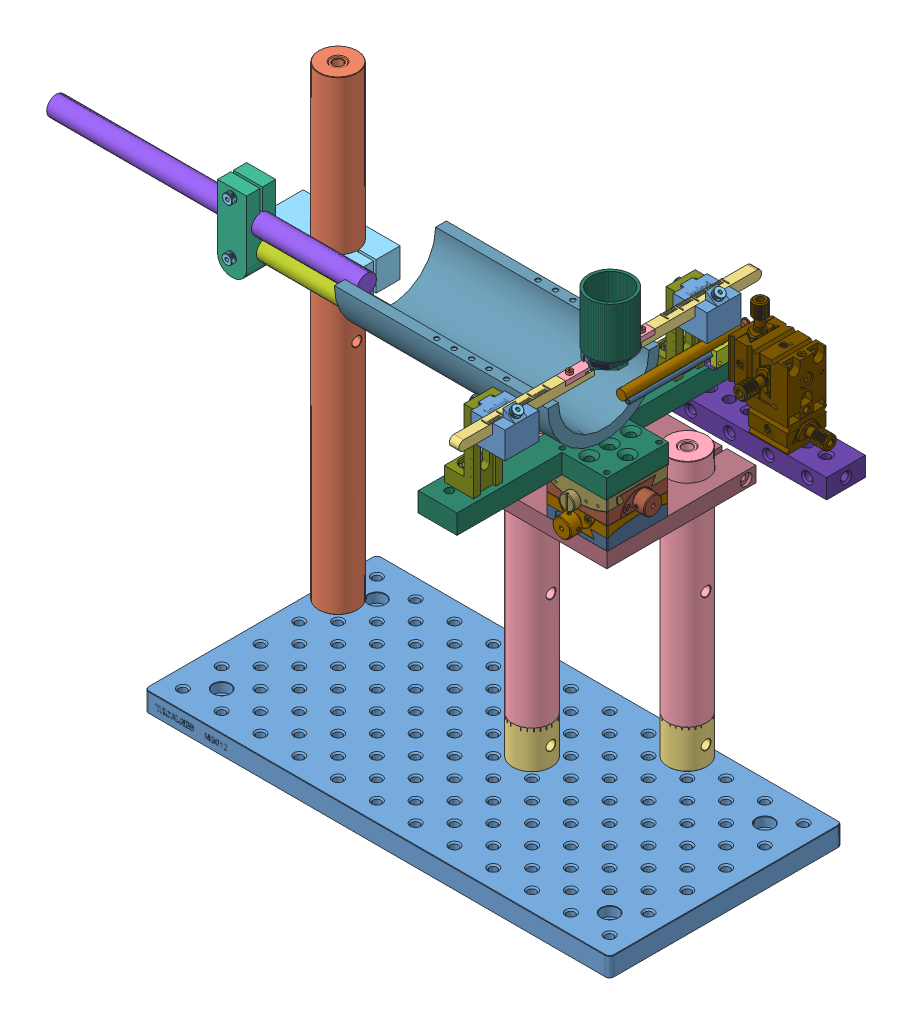
SolidWorks assembly Anesthetized Imaging Rig, configuration Default. Lengths in mm.
Overall size (450.58 317.5 198.19).
59 component instances, 33 part files, 37 mates.
Components (placement in the parent):
- THORLABS_baseplate_MB612-1: THORLABS_baseplate_MB612 [Default] at origin size (304.8 12.7 152.4)
- THORLABS_leg_RS12-1: THORLABS_leg_RS12 [Default] at (-139.7 12.7 -38.1) size (25.57 304.8 25.37)
- THORLABS_leg_RS1-1: THORLABS_leg_RS1 [Default] at (9.07 28.0621 -12.896) size (25.57 25.4 25.37)
- THORLABS_leg_RS1-2: THORLABS_leg_RS1 [Default] at (59.87 28.5325 -63.696) size (25.57 25.4 25.37)
- THORLABS_leg_RS6-1: THORLABS_leg_RS6 [Default] at (11.2798 112.6585 -13.2657) x (-0.009302 0 -0.999957) z (0.999957 0 -0.009302) size (25.37 152.4 25.57)
- THORLABS_leg_RS6-2: THORLABS_leg_RS6 [Default] at (62.0872 113.887 -64.0839) x (0.003562 0 -0.999994) z (0.999994 0 0.003562) size (25.37 152.4 25.57)
- bar_clamp_2-1: bar_clamp_2 [Default] at (-147.32 216.8443 -38.1) x (0 0 -1) z (-1 0 0) size (33.02 19.05 63.5)
- bar_clamp_1-1: bar_clamp_1 [Default] at (-173.6219 195.8875 -12.165) x (0 0 -1) z (1 0 0) size (19.05 50.8 19.05)
- horizontal_bar_2-1: horizontal_bar_2 [Default] at (-160.884 213.6676 -12.1346) x (0 -0.063873 0.997958) z (1 0 0) size (12.7 12.7 152.4)
- horizontal_bar_1-3: horizontal_bar_1 [Default] at (-298.1789 226.3675 -12.165) x (0 0 -1) z (1 0 0) size (12.7 12.7 203.2)
- GOH-40A51UU-1: GOH-40A51UU [Default] at (64.8145 124.6763 -9.8152) x (0 0 1) z (0 -1 0) size (50.27 46.7 15)
  - GOH-8UU-C1B-S02-1: GOH-8UU-C1B-S02 [Default] at origin size (50 40 12.5)
  - GOH-8UU-C1B-S01-1: GOH-8UU-C1B-S01 [Default] x (0 1 0) z (0 0 1) size (46.7 40.57 13)
- GOH-40A35RUU-1: GOH-40A35RUU [Default] at (70.0565 196.9888 -9.6675) x (-1 0 0) z (0 1 0) size (50.47 46.7 16)
  - GOH40A35RUU-M02-13001-S02-1: GOH40A35RUU-M02-13001-S02 [Default] at origin size (50 40 13.5)
  - GOH40A35RUU-M02-13001-S01-1: GOH40A35RUU-M02-13001-S01 [Default] at origin size (40.85 46.7 14)
- gonio_platform-3: gonio_platform [Default] at (35.95 166.2256 -38.45) size (97.5 10 97.5)
- tray-1: tray [Default] at (64.7511 264.1373 -15.4304) x (0 0 -1) z (-1 0 0) size (73.33 36.66 139.7)
- headbar_platform-1: headbar_platform [Default] at (31.035 205.2247 10.5881) size (54.61 12.7 178.16)
- headbar_post-1: headbar_post [Default] at (34.0613 217.9514 46.9863) size (19.05 50.8 19.07)
- headbar_post-2: headbar_post [Default] at (34.0613 218.2062 -85.4493) size (19.05 50.8 19.07)
- horizontal support-1: horizontal support [Default] at (78.5112 190.7326 -88.729) x (0.999996 0 -0.00275) z (0.00275 0 0.999996) size (127 12.7 25.4)
- MT-XYZ-1: MT-XYZ [Default] at (116.3607 203.4326 -88.7982) x (0 0 -1) z (0 -1 0) size (45.44 54.1 66.8)
- headbar finished assem-1: headbar finished assem [Default] at (64.2238 260.2066 67.755) x (0 0 -1) z (1 0 0) size (88.9 24.55 25.25)
  - bar rest-1: bar rest [Default] at origin size (22.23 22.61 24.77)
  - 91292A003_TYPE 18-8 SS SOCKET HEAD CAP SCREW-1: 91292A003_TYPE 18-8 SS SOCKET HEAD CAP SCREW [91292A003] at (53.4332 5.7455 0) x (1 0 0) z (0 -1 0) size (3.8 3.8 5.09)
  - headbar-1: headbar [Default] at (115.3465 -57.3797 -49.0764) x (0 0 1) z (-1 0 0) size (6.4 6.86 88.9)
    - headpost holder-1: headpost holder [Default] at (49.0764 62.9677 48.5529) x (0 1 0) z (0 0 1) size (6.86 6.35 88.9)
    - headbar clamp-1: headbar clamp [Default] at (49.0764 64.2202 58.1033) x (0 0 1) z (-1 0 0) size (19.1 3.05 6.4)
  - 96125A301_NICKEL ALLOY SHOULDER SCREW-1: 96125A301_NICKEL ALLOY SHOULDER SCREW [96125A301] at (10.7798 13.9746 8.8593) x (1 0 0) z (0 0.842271 0.539054) size (6.35 6.35 10.69)
- headbar finished flipped-1: headbar finished flipped [Default] at (64.2238 260.4614 -64.6806) x (0 0 -1) z (1 0 0) size (88.9 24.86 25.74)
  - bar rest-1: bar rest [Default] at origin size (22.23 22.61 24.77)
  - 91292A003_TYPE 18-8 SS SOCKET HEAD CAP SCREW-1: 91292A003_TYPE 18-8 SS SOCKET HEAD CAP SCREW [91292A003] at (-31.8888 5.7455 0) x (1 0 0) z (0 -1 0) size (3.8 3.8 5.09)
  - headbar-1: headbar [Default] at (-93.8022 -57.3797 49.0764) x (0 0 -1) z (1 0 0) size (6.4 6.86 88.9)
    - headpost holder-1: headpost holder [Default] at (49.0764 62.9677 48.5529) x (0 1 0) z (0 0 1) size (6.86 6.35 88.9)
    - headbar clamp-1: headbar clamp [Default] at (49.0764 64.2202 58.1033) x (0 0 1) z (-1 0 0) size (19.1 3.05 6.4)
  - 96125A301_NICKEL ALLOY SHOULDER SCREW-1: 96125A301_NICKEL ALLOY SHOULDER SCREW [96125A301] at (10.7798 13.9746 8.8593) x (0.978373 0.111501 -0.174221) z (0 0.842271 0.539054) size (6.35 6.35 10.69)
- visual cortex headpost-1: visual cortex headpost [Default] at (82.7466 266.1019 -47.6087) x (0 0 -1) z (1 0 0) size (32.4 1.2 14.66)
- 96125A301_NICKEL ALLOY SHOULDER SCREW-1: 96125A301_NICKEL ALLOY SHOULDER SCREW [96125A301] at (-173.99 207.3193 0.535) size (6.35 6.35 10.69)
- 96125A301_NICKEL ALLOY SHOULDER SCREW-2: 96125A301_NICKEL ALLOY SHOULDER SCREW [96125A301] at (-173.6694 241.6078 0.535) size (6.35 6.35 10.69)
- 96125A301_NICKEL ALLOY SHOULDER SCREW-3: 96125A301_NICKEL ALLOY SHOULDER SCREW [96125A301] at (-173.99 207.3193 -57.785) x (-1 0 0) z (0 0 -1) size (6.35 6.35 10.69)
- 96125A301_NICKEL ALLOY SHOULDER SCREW-4: 96125A301_NICKEL ALLOY SHOULDER SCREW [96125A301] at (40.4113 228.7176 -75.9243) x (0.999784 0 -0.02077) z (0 1 0) size (6.35 6.35 10.69)
- 96125A301_NICKEL ALLOY SHOULDER SCREW-5: 96125A301_NICKEL ALLOY SHOULDER SCREW [96125A301] at (40.4113 226.4363 56.5113) x (1 0 0) z (0 1 0) size (6.35 6.35 10.69)
- 96125A301_NICKEL ALLOY SHOULDER SCREW-6: 96125A301_NICKEL ALLOY SHOULDER SCREW [96125A301] at (44.4354 264.9064 -75.9243) x (0 0 1) z (-1 0 0) size (6.35 6.35 10.69)
- 96125A301_NICKEL ALLOY SHOULDER SCREW-7: 96125A301_NICKEL ALLOY SHOULDER SCREW [96125A301] at (43.5478 264.6516 56.5113) x (0 0 1) z (-1 0 0) size (6.35 6.35 10.69)
- 96125A301_NICKEL ALLOY SHOULDER SCREW-8: 96125A301_NICKEL ALLOY SHOULDER SCREW [96125A301] at (40.4113 221.0997 -88.6243) x (0 0 -1) z (0 1 0) size (6.35 6.35 10.69)
- tube holder assem-1: tube holder assem [Default] at (74.9276 239.8069 -76.4776) x (0 0 1) z (-1 0 0) size (82.13 15.87 10.25)
  - tube holder-1: tube holder [Default] at (2.0924 2.1909 -3.1299) size (12.57 9.53 4)
  - tube clip-1: tube clip [Default] at (6.1681 -3.5321 0.7457) x (-1 -0.000016 0) z (0 0 -1) size (6.35 11.43 6.35)
  - tube assem-2: tube assem [Default] at (65.772 8.7165 1.9056) x (0 0 -1) z (-1 0 0) size (10.25 15.76 82.13)
    - long tube-1: long tube [Default] x (-1 0 0) z (0 0 1) size (6.35 6.35 76.2)
    - short tube-1: short tube [Default] at (0.7155 5.1856 65.4617) x (0.872865 -0.487962 0) z (0 0 -1) size (3.17 3.17 61.98)
    - LUER LOCK-3: LUER LOCK [Default] at (0 0 65.6348) size (7.25 7.25 12.43)
    - LUER LOCK-4: LUER LOCK [Default] at (0.7123 7.0161 65.6348) x (0.707107 -0.707107 0) z (0 0 1) size (7.25 7.25 12.43)
    - 1946K240_MARINE-RATED COPPER-NICKEL PIPE FITTING-1: 1946K240_MARINE-RATED COPPER-NICKEL PIPE FITTING [1946K24] at (0.7123 10.6533 67.5596) x (-1 0 0) z (0 -0.707107 0.707107) size (3.18 5.73 4.6)
    - 1946K240_MARINE-RATED COPPER-NICKEL PIPE FITTING-2: 1946K240_MARINE-RATED COPPER-NICKEL PIPE FITTING [1946K24] at (0.7155 1.5483 69.6519) x (-1 0 0) z (0 0.707107 -0.707107) size (3.18 5.73 4.6)
    - tube small-1: tube small [Default] at (0.7123 7.0161 70.612) size (3.17 3.17 5.59)
- light proofing-crown-2: light proofing-crown [Default] at (15.6055 268.0204 -67.6381) x (0 0 1) z (0 1 0) size (27.95 27.95 6.18)
- light proofing-cylinder-1: light proofing-cylinder [Default] at (-16.2472 307.3009 -56.3161) x (1 0 0) z (0 -1 0) size (28.2 28.2 33)
Mates (geometry in assembly coordinates):
- Concentric1: concentric aligned: circle of THORLABS_baseplate_MB612-1; circle of THORLABS_leg_RS12-1
- Concentric2: concentric anti-aligned: circle of THORLABS_baseplate_MB612-1; circle of THORLABS_leg_RS1-1
- Concentric3: concentric anti-aligned: circle of THORLABS_baseplate_MB612-1; circle of THORLABS_leg_RS1-2
- Concentric4: concentric anti-aligned: circle of THORLABS_leg_RS1-1; circle of THORLABS_leg_RS6-1
- Concentric5: concentric anti-aligned: circle of THORLABS_leg_RS1-2; circle of THORLABS_leg_RS6-2
- Concentric8: concentric aligned: circle of THORLABS_leg_RS12-1; circle of bar_clamp_2-1
- Concentric9: concentric anti-aligned: circle of bar_clamp_2-1; circle of bar_clamp_1-1
- Concentric11: concentric aligned: cylinder of bar_clamp_1-1 through (-183.1479 226.3675 -12.165) axis (1 0 0) radius 6.35; circle of horizontal_bar_1-3
- Concentric30: concentric anti-aligned: circle of THORLABS_leg_RS6-1; circle of gonio_platform-3
- Lock1: lock: unknown of headbar_platform-1; unknown of headbar_post-2
- Lock2: lock: unknown of headbar_platform-1; unknown of headbar_post-1
- Concentric33: concentric anti-aligned: circle of headbar_platform-1; circle of horizontal support-1
- Tangent1: tangent anti-aligned: cylinder of horizontal_bar_2-1 through (-8.484 213.6676 -12.1346) axis (-1 0 0) radius 6.35; cylinder of horizontal_bar_1-3 through (-94.9789 226.3675 -12.165) axis (-1 0 0) radius 6.35
- Coincident3: coincident anti-aligned: plane of headbar_post-1 through (53.1113 217.9514 66.0363) normal (1 0 0); plane of headbar finished assem-1/bar rest-1 through (53.1113 268.9696 45.53) normal (-1 0 0)
- Concentric36: concentric aligned: circle of headbar_post-1; circle of headbar finished assem-1/bar rest-1
- Concentric37: concentric aligned: circle of headbar_post-2; circle of headbar finished flipped-1/bar rest-1
- Coincident5: coincident anti-aligned: plane of headbar_post-2 through (53.1113 218.2062 -66.3993) normal (1 0 0); plane of headbar finished flipped-1/bar rest-1 through (53.1113 269.2244 -86.9056) normal (-1 0 0)
- Concentric40: concentric anti-aligned: circle of bar_clamp_1-1; circle of 96125A301_NICKEL ALLOY SHOULDER SCREW-1
- Coincident6: coincident anti-aligned: plane of bar_clamp_1-1 through (-183.1469 246.6875 -2.64) normal (0 0 1); plane of 96125A301_NICKEL ALLOY SHOULDER SCREW-1 through (-173.99 204.1443 -2.64) normal (0 0 -1)
- Concentric41: concentric anti-aligned: circle of bar_clamp_1-1; circle of 96125A301_NICKEL ALLOY SHOULDER SCREW-2
- Coincident7: coincident anti-aligned: plane of bar_clamp_1-1 through (-183.1469 246.6875 -2.64) normal (0 0 1); plane of 96125A301_NICKEL ALLOY SHOULDER SCREW-2 through (-173.6694 238.4328 -2.64) normal (0 0 -1)
- Concentric43: concentric anti-aligned: circle of bar_clamp_2-1; cone of 96125A301_NICKEL ALLOY SHOULDER SCREW-3 through (-173.99 207.3193 -47.4663) axis (0 0 1)
- Coincident10: coincident anti-aligned: plane of bar_clamp_2-1 through (-115.57 197.7943 -54.61) normal (0 0 -1); plane of 96125A301_NICKEL ALLOY SHOULDER SCREW-3 through (-173.99 204.1443 -54.61) normal (0 0 1)
- Concentric44: concentric anti-aligned: circle of headbar_post-2; circle of 96125A301_NICKEL ALLOY SHOULDER SCREW-4
- Concentric45: concentric anti-aligned: circle of headbar_post-1; circle of 96125A301_NICKEL ALLOY SHOULDER SCREW-5
- Concentric46: concentric anti-aligned: cylinder of headbar finished flipped-1/bar rest-1 through (50.5713 264.9064 -75.9243) axis (-1 0 0) radius 2.5527; circle of 96125A301_NICKEL ALLOY SHOULDER SCREW-6
- Concentric47: concentric anti-aligned: cylinder of headbar finished assem-1/bar rest-1 through (50.5713 264.6516 56.5113) axis (-1 0 0) radius 2.5527; circle of 96125A301_NICKEL ALLOY SHOULDER SCREW-7
- Concentric48: concentric anti-aligned: circle of headbar_platform-1; circle of 96125A301_NICKEL ALLOY SHOULDER SCREW-8
- Coincident11: coincident anti-aligned: plane of headbar_platform-1 through (31.035 217.9247 10.5881) normal (0 1 0); plane of 96125A301_NICKEL ALLOY SHOULDER SCREW-8 through (43.5863 217.9247 -88.6243) normal (0 -1 0)
- Concentric49: concentric anti-aligned: circle of horizontal support-1; circle of MT-XYZ-1
- Coincident12: coincident anti-aligned: plane of horizontal support-1 through (78.5112 203.4326 -88.729) normal (0 1 0); plane of MT-XYZ-1 through (90.9607 203.4326 -101.4982) normal (0 -1 0)
- Coincident16: coincident anti-aligned: plane of headbar finished assem-1/headbar-1/headbar clamp-1 through (67.4242 265.9041 6.9812) normal (0 0 -1); plane of visual cortex headpost-1 through (61.0463 267.3019 6.9812) normal (0 0 1)
- Coincident17: coincident anti-aligned: plane of headbar finished flipped-1/headbar-1/headbar clamp-1 through (64.2238 267.3019 -28.9817) normal (0 -1 0); plane of visual cortex headpost-1 through (82.7466 267.3019 -47.6087) normal (0 1 0)
- Concentric54: concentric aligned: circle of MT-XYZ-1; circle of tube holder assem-1/tube holder-1
- Coincident18: coincident anti-aligned: plane of MT-XYZ-1 through (78.0575 226.6228 -101.4982) normal (-1 0 0); plane of tube holder assem-1/tube holder-1 through (78.0575 241.9978 -74.3852) normal (1 0 0)
- Coincident19: coincident anti-aligned: plane of headbar finished flipped-1/bar rest-1 through (64.2238 260.4614 -86.9056) normal (0 0 -1); plane of tube holder assem-1/tube assem-2/LUER LOCK-3 through (73.022 248.5234 -86.9056) normal (0 0 1)
- Tangent3: tangent anti-aligned: plane of headbar finished flipped-1/bar rest-1 through (75.3363 251.6984 -86.9056) normal (0 -1 0); cylinder of tube holder assem-1/tube assem-2/long tube-1 through (73.022 248.5234 -86.9056) axis (0 0 1) radius 3.175
